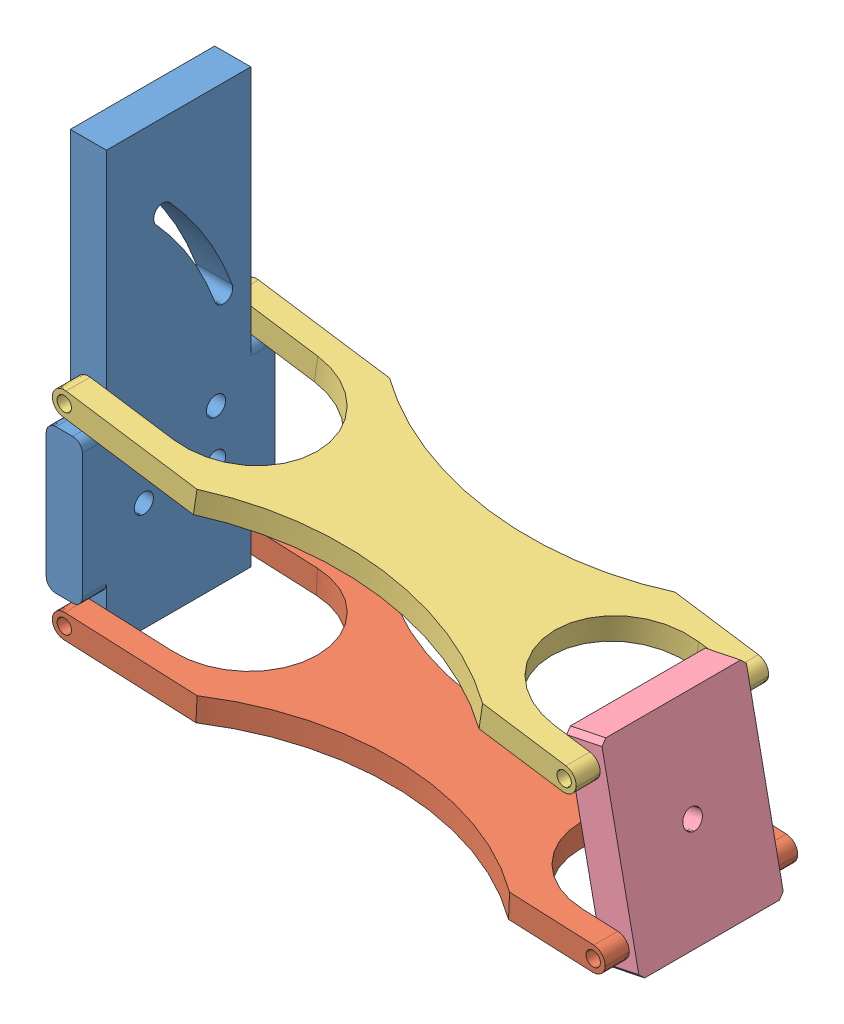
SolidWorks assembly Prototype1, configuration Default. Lengths in mm.
Overall size (300.54 242.69 101.6).
4 component instances, 4 part files, 4 mates.
Components (placement in the parent):
- mounting_plate-1: mounting_plate [Default] at (-204.1764 -111.665 183.6047) size (19.05 228.6 101.6)
- wishbone-bottom-1: wishbone-bottom [Default] at (-201.2776 -105.0263 196.3047) x (0 0 -1) z (0.99901 -0.044481 0) size (101.6 12.7 292.1)
- wishbone-top-1: wishbone-top [Default] at (-201.8696 -2.7075 196.3047) x (0 0 -1) z (0.989033 -0.147693 0) size (101.6 12.7 279.4)
- wheel_plate-1: wheel_plate [Default] at (77.7003 -125.7511 183.6047) x (0.979505 0.201421 0) z (0 0 1) size (19.05 101.6 76.2)
Mates (geometry in assembly coordinates):
- Coincident2: coincident aligned: circle of mounting_plate-1; circle of wishbone-bottom-1
- Coincident3: coincident aligned: circle of mounting_plate-1; circle of wishbone-top-1
- Coincident6: coincident aligned: circle of wishbone-bottom-1; circle of wheel_plate-1
- Coincident7: coincident aligned: circle of wishbone-top-1; circle of wheel_plate-1
